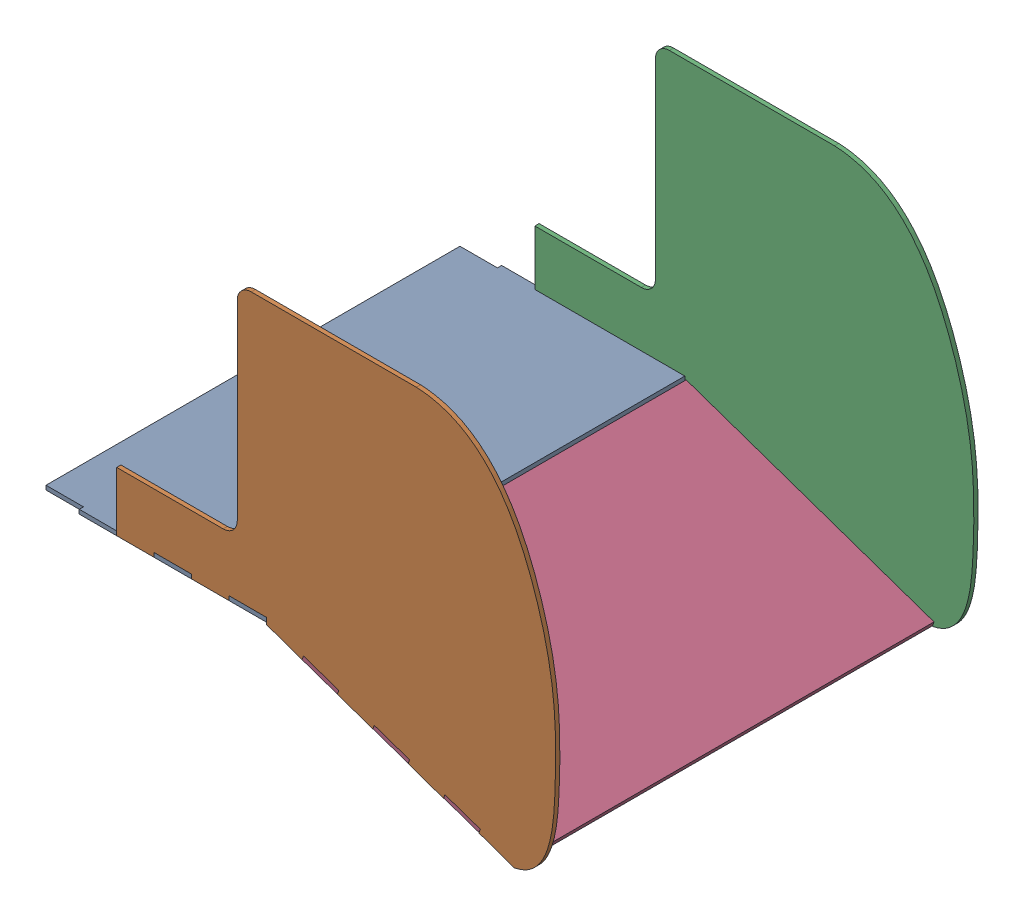
SolidWorks assembly FINAL, configuration Default. Lengths in mm.
Overall size (367.05 282.22 301.07).
5 component instances, 4 part files, 4 mates.
Components (placement in the parent):
- placa-3: placa [Default] at (-104.5076 17.8118 2.7979) x (0 0 -1) z (0 -1 0) size (301.07 160.28 3)
- LADOCAJA-16: LADOCAJA [Default] at (139.2351 16.3901 150.3351) x (0 0 1) z (-1 0 0) size (3 261.79 313.65)
- LADOCAJA-17: LADOCAJA [Default] at (139.2351 16.3901 -147.7393) x (0 0 1) z (-1 0 0) size (3 261.79 313.65)
- placanaja-1: placanaja [Predeterminado] at (153.6015 -28.7527 14.1489) x (0 0 -1) z (0.945056 -0.326908 0) size (301.07 3 186.9)
- soporteizq-1: soporteizq [Predeterminado] at (-59.1696 -68.9123 -269.6703) x (0 0 -1) z (1 0 0) size (133.23 83.72 79.38)
Mates (geometry in assembly coordinates):
- Coincidente7: coincident: line of assembly; point of assembly; line of LADOCAJA-16 through (57.7821 4.3925 153.3351) axis (0.326908 0.945056 0); moEndPointRef_w of placanaja-1
- Coincidente8: coincident: line of placa-3 through (-20.9649 17.8118 153.3351) axis (-1 0 0); line of LADOCAJA-16 through (-47.6649 17.8118 153.3351) axis (1 0 0)
- Paralelo1: parallel anti-aligned: plane of placa-3 through (-104.5076 14.8118 2.7979) normal (0 -1 0); plane of soporteizq-1 through (-37.7669 14.8118 -55.2367) normal (0 1 0)
- Coincidente15: coincident anti-aligned: plane of placa-3 through (-104.5076 14.8118 2.7979) normal (0 -1 0); plane of soporteizq-1 through (-37.7669 14.8118 -55.2367) normal (0 1 0)
